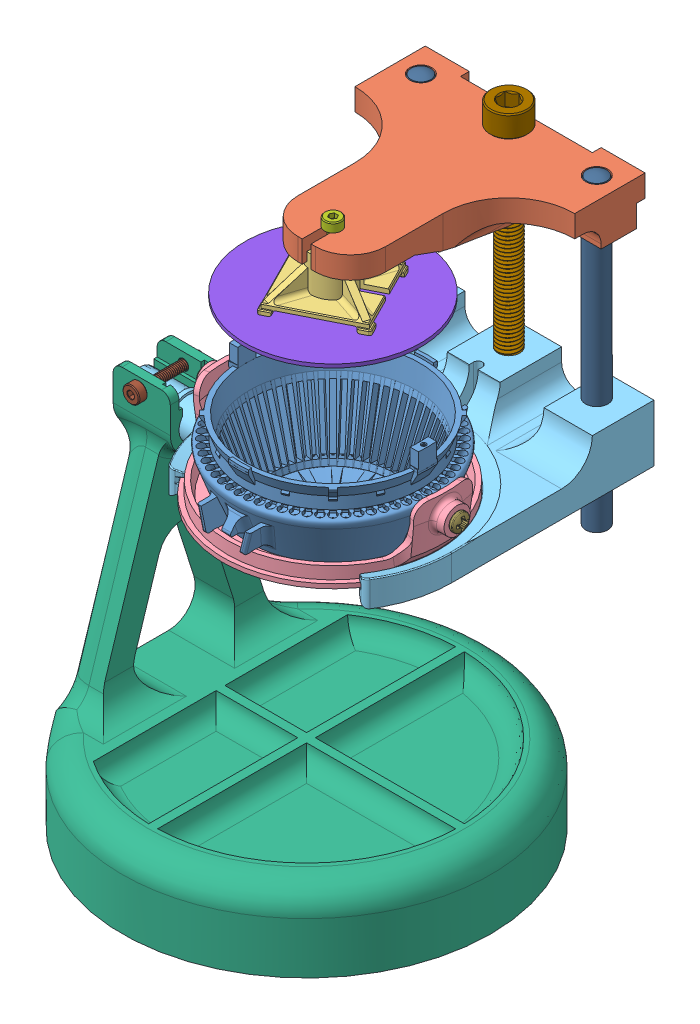
SolidWorks assembly rat_jig_assembly, configuration Default. Lengths in mm.
Overall size (80.2 126.68 87.92).
14 component instances, 12 part files, 28 mates.
Components (placement in the parent):
- rat_shuttle_drive_body_bilateral_vta-1: rat_shuttle_drive_body_bilateral_vta [Default] at origin size (48.6 34.18 50)
- eib_holder_top-1: eib_holder_top [Default] at (0 61.755 0) size (50 11.02 52)
- eib256_holder-1: eib256_holder [Default] at (0 53.755 0) x (0.949652 0 0.313307) z (-0.313307 0 0.949652) size (27 11 27)
- drive_body_holder_inner_ring-1: drive_body_holder_inner_ring [Default] at (0 13.0104 0) size (56.5 14.62 50)
- drive_body_holder_outer_ring-1: drive_body_holder_outer_ring [Default] at (0 13.0104 0) size (71.07 14.5 61)
- jig_base_big_rat-1: jig_base_big_rat [Default] at (-6 13.0104 0) x (0 0 1) z (-1 0 0) size (83.84 75.7 80.2)
- socket head cap screw_am-1: socket head cap screw_am [B18.3.1M - 2 x 0.4 x 20 Hex SHCS -- 16SHX] at (0 68.755 0) x (0 -1 0) z (0 0 1) size (22 3.8 3.8)
- eib_standin-1: eib_standin [Default] at (0 52.955 0) x (0.999998 0 0.00221) z (-0.00221 0 0.999998) size (40 0.8 40)
- 91290A201_BLACK-OXIDE CLASS 12.9 SOCKET HEAD CAP SCREW-1: 91290A201_BLACK-OXIDE CLASS 12.9 SOCKET HEAD CAP SCREW [91290A201] at (0 -3.245 -40) x (1 0 0) z (0 -1 0) size (8.5 8.5 75.77)
- 91595A399_METRIC ALLOY STEEL DOWEL PIN-1: 91595A399_METRIC ALLOY STEEL DOWEL PIN [91595A399] at (20 32.405 -40) x (0 1 0) z (0 0 1) size (70 5 5)
- 91595A399_METRIC ALLOY STEEL DOWEL PIN-2: 91595A399_METRIC ALLOY STEEL DOWEL PIN [91595A399] at (-20 32.405 -40) x (0 1 0) z (0 0 1) size (70 5 5)
- 91292A835_TYPE 18-8 SS SOCKET HEAD CAP SCREW-1: 91292A835_TYPE 18-8 SS SOCKET HEAD CAP SCREW [91292A835] at (-38 18.5104 -8) x (-0.923728 -0.383049 0) z (0 0 -1) size (3.8 3.8 16.14)
- 92005A023_METRIC PAN HEAD PHILLIPS MACHINE SCREW-1: 92005A023_METRIC PAN HEAD PHILLIPS MACHINE SCREW [92005A023] at (22.25 22.9 0) x (0 0 -1) z (1 0 0) size (4 4 7.58)
- 92005A023_METRIC PAN HEAD PHILLIPS MACHINE SCREW-2: 92005A023_METRIC PAN HEAD PHILLIPS MACHINE SCREW [92005A023] at (-22.25 22.9 0) x (0 0 1) z (-1 0 0) size (4 4 7.58)
Mates (geometry in assembly coordinates):
- Coincident4: coincident: plane of assembly; circle of assembly; plane of eib_holder_top-1 through (0 66.755 0) normal (0 1 0); circle of 91595A399_METRIC ALLOY STEEL DOWEL PIN-1
- Concentric4: concentric: cylinder of assembly; cylinder of assembly; cylinder of eib_holder_top-1 through (20 66.755 -40) axis (0 -1 0) radius 2.5; cylinder of 91595A399_METRIC ALLOY STEEL DOWEL PIN-1 through (20 -2.595 -40) axis (0 1 0) radius 2.5
- Coincident5: coincident: plane of assembly; plane of assembly; plane of eib_holder_top-1 through (0 66.755 0) normal (0 1 0); plane of 91290A201_BLACK-OXIDE CLASS 12.9 SOCKET HEAD CAP SCREW-1 through (0 66.755 -40) normal (0 -1 0)
- Concentric5: concentric: cylinder of assembly; cylinder of assembly; cylinder of eib_holder_top-1 through (0 66.755 -40) axis (0 -1 0) radius 2.5; cylinder of 91290A201_BLACK-OXIDE CLASS 12.9 SOCKET HEAD CAP SCREW-1 through (0 71.755 -40) axis (0 -1 0) radius 4.25
- Concentric6: concentric: cylinder of assembly; cylinder of assembly; cylinder of eib_holder_top-1 through (-20 66.755 -40) axis (0 -1 0) radius 2.5; cylinder of 91595A399_METRIC ALLOY STEEL DOWEL PIN-2 through (-20 -2.595 -40) axis (0 1 0) radius 2.5
- Coincident6: coincident: plane of assembly; circle of assembly; plane of eib_holder_top-1 through (0 66.755 0) normal (0 1 0); circle of 91595A399_METRIC ALLOY STEEL DOWEL PIN-2
- Concentric8: concentric: cylinder of ? through (0 14.0104 0) axis (0 -1 0) radius 25; cylinder of ? through (0 13.0104 0) axis (0 -1 0) radius 25.2
- Concentric12: concentric: cylinder of ? through (-44 13.0104 0) axis (1 0 0) radius 4; cylinder of jig_base_big_rat-1 through (-44 13.0104 0) axis (1 0 0) radius 4
- Coincident8: coincident: plane of ? through (0 13.0104 0) normal (0 -1 0); plane of ? through (-25.2 13.0104 0) normal (0 1 0)
- Coincident9: coincident: plane of ? through (-44 13.0104 0) normal (-1 0 0); plane of jig_base_big_rat-1 through (-44 13.0104 1.5875) normal (-1 0 0)
- Concentric13: concentric: circle of ?; cylinder of 91595A399_METRIC ALLOY STEEL DOWEL PIN-2 through (-20 -2.595 -40) axis (0 1 0) radius 2.5
- Concentric14: concentric: cylinder of assembly; cylinder of assembly; cylinder of eib_holder_top-1 through (0 66.755 0) axis (0 -1 0) radius 1; cylinder of socket head cap screw_am-1 through (0 100.505 0) axis (0 1 0) radius 1
- Coincident10: coincident: plane of assembly; plane of assembly; plane of eib_holder_top-1 through (0 66.755 0) normal (0 1 0); plane of socket head cap screw_am-1 through (1.9 66.755 0) normal (0 -1 0)
- Concentric15: concentric: cylinder of assembly; circle of assembly; cylinder of eib256_holder-1 through (0 63.755 0) axis (0 -1 0) radius 5; circle of eib_standin-1
- Concentric16: concentric: cylinder of assembly; cylinder of assembly; cylinder of eib256_holder-1 through (0 55.755 0) axis (0 -1 0) radius 1; cylinder of socket head cap screw_am-1 through (0 100.505 0) axis (0 1 0) radius 1
- Coincident11: coincident: plane of assembly; plane of assembly; plane of eib_holder_top-1 through (0 63.755 0) normal (0 -1 0); plane of eib256_holder-1 through (0 63.755 0) normal (0 1 0)
- Coincident12: coincident: plane of assembly; plane of assembly; plane of eib256_holder-1 through (0 53.755 0) normal (0 -1 0); plane of eib_standin-1 through (0 53.755 0) normal (0 1 0)
- Concentric17: concentric: circle of assembly; circle of assembly; circle of rat_shuttle_drive_body_bilateral_vta-1; circle of eib_standin-1
- Concentric18: concentric: circle of ?; circle of eib_standin-1
- Parallel1: parallel: line of ? through (-21.136 13.0104 -4.7744) axis (0 0 1); plane of jig_base_big_rat-1 through (-31 13.0104 0) normal (1 0 0)
- Tangent2: tangent: cone of ?; cylinder of rat_shuttle_drive_body_bilateral_vta-1 through (0 8 0) axis (0 -1 0) radius 352.4979
- Perpendicular1: perpendicular: line of assembly; plane of assembly; line of rat_shuttle_drive_body_bilateral_vta-1 through (-1 18.9987 24.1649) axis (1 0 0); plane of jig_base_big_rat-1 through (-31 13.0104 0) normal (1 0 0)
- Concentric22: concentric: cylinder of assembly; cylinder of assembly; cylinder of jig_base_big_rat-1 through (-38 18.5104 6) axis (0 0 -1) radius 1.2; cylinder of 91292A835_TYPE 18-8 SS SOCKET HEAD CAP SCREW-1 through (-38 18.5104 8) axis (0 0 -1) radius 1.9
- Coincident19: coincident: plane of assembly; plane of assembly; plane of jig_base_big_rat-1 through (-31 21.0104 6) normal (0 0 1); plane of 91292A835_TYPE 18-8 SS SOCKET HEAD CAP SCREW-1 through (-38 18.5104 6) normal (0 0 -1)
- Coincident20: coincident: plane of ? through (28.25 22.9 0) normal (1 0 0); plane of 92005A023_METRIC PAN HEAD PHILLIPS MACHINE SCREW-1 through (28.25 22.9 0) normal (-1 0 0)
- Concentric23: concentric: cylinder of ? through (28.25 22.9 0) axis (-1 0 0) radius 3; cylinder of 92005A023_METRIC PAN HEAD PHILLIPS MACHINE SCREW-1 through (22.25 22.9 0) axis (-1 0 0) radius 2
- Coincident21: coincident: plane of ? through (-28.25 22.9 0) normal (-1 0 0); plane of 92005A023_METRIC PAN HEAD PHILLIPS MACHINE SCREW-2 through (-28.25 22.9 0) normal (1 0 0)
- Concentric24: concentric: cylinder of ? through (-28.25 22.9 0) axis (1 0 0) radius 3; cylinder of 92005A023_METRIC PAN HEAD PHILLIPS MACHINE SCREW-2 through (-22.25 22.9 0) axis (1 0 0) radius 2
